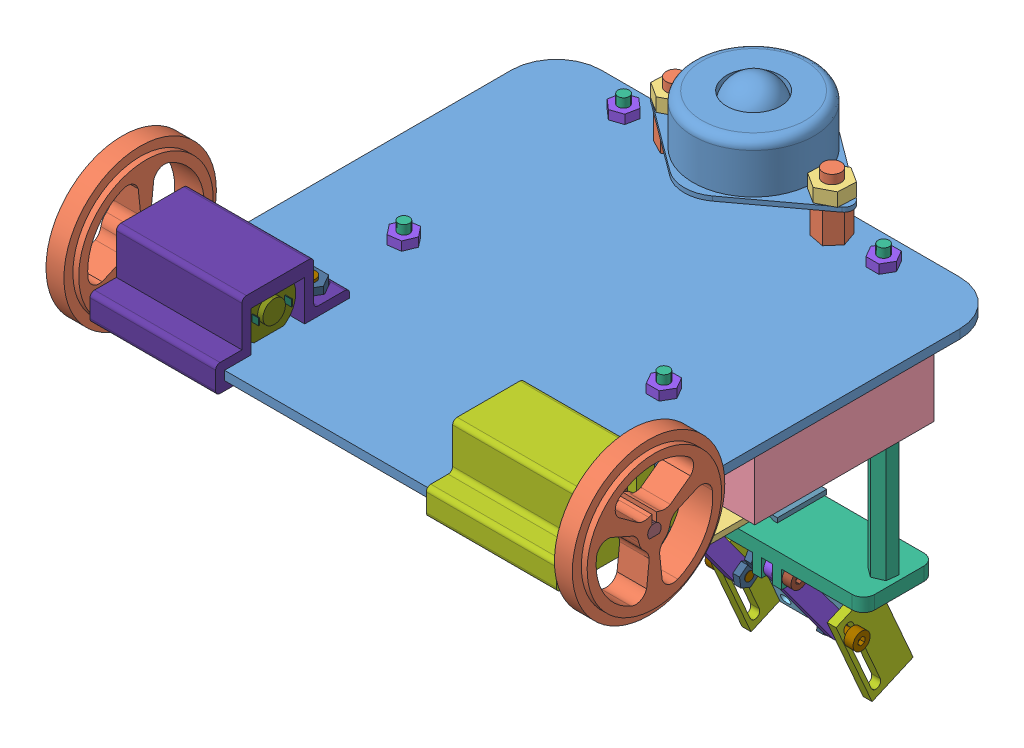
SolidWorks assembly car (old), configuration 默认. Lengths in mm.
Overall size (120 119.73 122.15).
122 component instances, 83 part files, 125 mates.
Components (placement in the parent):
- car  baseplate-3: car  baseplate [默认] at (1.828 99 14.0699) x (0 0 -1) z (0 1 0) size (100 100 2)
- N20 wheel -1: N20 wheel  [默认] at (61.828 106 52.1949) x (0 0 1) z (0 -1 0) size (34 8.6 34)
- N20 wheel -2: N20 wheel  [默认] at (-58.172 106 52.1949) x (0 0 1) z (0 1 0) size (34 8.6 34)
- raspberrypi3.stp-1: raspberrypi3.stp [默认] at (-8.172 78.45 0.8199) x (-1 0 0) z (0 0 -1) size (90.89 18.8 58.5)
  - Raspberry Pi 3.stp-1: Raspberry Pi 3.stp [默认] at origin size (90.89 18.8 58.5)
    - Raspberry Pi 3_1.stp-1: Raspberry Pi 3_1.stp [默认] at origin size (85 1.3 56)
    - Raspberry Pi 3_1_1.stp-1: Raspberry Pi 3_1_1.stp [默认] at origin size (14 1 14)
    - Raspberry Pi 3_2.stp-1: Raspberry Pi 3_2.stp [默认] at origin size (8.5 1 8.5)
    - Raspberry Pi 3_3.stp-1: Raspberry Pi 3_3.stp [默认] at origin size (12 1 12)
    - Raspberry Pi 3_4.stp-1: Raspberry Pi 3_4.stp [默认] at origin size (0.64 10.23 0.64)
    - Raspberry Pi 3_5.stp-1: Raspberry Pi 3_5.stp [默认] at origin size (0.64 10.23 0.64)
    - Raspberry Pi 3_6.stp-1: Raspberry Pi 3_6.stp [默认] at origin size (0.64 10.23 0.64)
    - Raspberry Pi 3_7.stp-1: Raspberry Pi 3_7.stp [默认] at origin size (0.64 10.23 0.64)
    - Raspberry Pi 3_8.stp-1: Raspberry Pi 3_8.stp [默认] at origin size (0.64 10.23 0.64)
    - Raspberry Pi 3_9.stp-1: Raspberry Pi 3_9.stp [默认] at origin size (0.64 10.23 0.64)
    - Raspberry Pi 3_10.stp-1: Raspberry Pi 3_10.stp [默认] at origin size (0.64 10.23 0.64)
    - Raspberry Pi 3_11.stp-1: Raspberry Pi 3_11.stp [默认] at origin size (0.64 10.23 0.64)
    - Raspberry Pi 3_12.stp-1: Raspberry Pi 3_12.stp [默认] at origin size (0.64 10.23 0.64)
    - Raspberry Pi 3_13.stp-1: Raspberry Pi 3_13.stp [默认] at origin size (0.64 10.23 0.64)
    - Raspberry Pi 3_14.stp-1: Raspberry Pi 3_14.stp [默认] at origin size (0.64 10.23 0.64)
    - Raspberry Pi 3_15.stp-1: Raspberry Pi 3_15.stp [默认] at origin size (0.64 10.23 0.64)
    - Raspberry Pi 3_16.stp-1: Raspberry Pi 3_16.stp [默认] at origin size (0.64 10.23 0.64)
    - Raspberry Pi 3_17.stp-1: Raspberry Pi 3_17.stp [默认] at origin size (0.64 10.23 0.64)
    - Raspberry Pi 3_18.stp-1: Raspberry Pi 3_18.stp [默认] at origin size (0.64 10.23 0.64)
    - Raspberry Pi 3_19.stp-1: Raspberry Pi 3_19.stp [默认] at origin size (0.64 10.23 0.64)
    - Raspberry Pi 3_20.stp-1: Raspberry Pi 3_20.stp [默认] at origin size (0.64 10.23 0.64)
    - Raspberry Pi 3_21.stp-1: Raspberry Pi 3_21.stp [默认] at origin size (0.64 10.23 0.64)
    - Raspberry Pi 3_22.stp-1: Raspberry Pi 3_22.stp [默认] at origin size (0.64 10.23 0.64)
    - Raspberry Pi 3_23.stp-1: Raspberry Pi 3_23.stp [默认] at origin size (0.64 10.23 0.64)
    - Raspberry Pi 3_24.stp-1: Raspberry Pi 3_24.stp [默认] at origin size (0.64 10.23 0.64)
    - Raspberry Pi 3_25.stp-1: Raspberry Pi 3_25.stp [默认] at origin size (0.64 10.23 0.64)
    - Raspberry Pi 3_26.stp-1: Raspberry Pi 3_26.stp [默认] at origin size (0.64 10.23 0.64)
    - Raspberry Pi 3_27.stp-1: Raspberry Pi 3_27.stp [默认] at origin size (0.64 10.23 0.64)
    - Raspberry Pi 3_28.stp-1: Raspberry Pi 3_28.stp [默认] at origin size (0.64 10.23 0.64)
    - Raspberry Pi 3_29.stp-1: Raspberry Pi 3_29.stp [默认] at origin size (0.64 10.23 0.64)
    - Raspberry Pi 3_30.stp-1: Raspberry Pi 3_30.stp [默认] at origin size (0.64 10.23 0.64)
    - Raspberry Pi 3_31.stp-1: Raspberry Pi 3_31.stp [默认] at origin size (0.64 10.23 0.64)
    - Raspberry Pi 3_32.stp-1: Raspberry Pi 3_32.stp [默认] at origin size (0.64 10.23 0.64)
    - Raspberry Pi 3_33.stp-1: Raspberry Pi 3_33.stp [默认] at origin size (0.64 10.23 0.64)
    - Raspberry Pi 3_34.stp-1: Raspberry Pi 3_34.stp [默认] at origin size (0.64 10.23 0.64)
    - Raspberry Pi 3_35.stp-1: Raspberry Pi 3_35.stp [默认] at origin size (0.64 10.23 0.64)
    - Raspberry Pi 3_36.stp-1: Raspberry Pi 3_36.stp [默认] at origin size (0.64 10.23 0.64)
    - Raspberry Pi 3_37.stp-1: Raspberry Pi 3_37.stp [默认] at origin size (0.64 10.23 0.64)
    - Raspberry Pi 3_38.stp-1: Raspberry Pi 3_38.stp [默认] at origin size (0.64 10.23 0.64)
    - Raspberry Pi 3_39.stp-1: Raspberry Pi 3_39.stp [默认] at origin size (0.64 10.23 0.64)
    - Raspberry Pi 3_40.stp-1: Raspberry Pi 3_40.stp [默认] at origin size (0.64 10.23 0.64)
    - Raspberry Pi 3_41.stp-1: Raspberry Pi 3_41.stp [默认] at origin size (0.64 10.23 0.64)
    - Raspberry Pi 3_42.stp-1: Raspberry Pi 3_42.stp [默认] at origin size (0.64 10.23 0.64)
    - Raspberry Pi 3_43.stp-1: Raspberry Pi 3_43.stp [默认] at origin size (0.64 10.23 0.64)
    - Raspberry Pi 3_44.stp-1: Raspberry Pi 3_44.stp [默认] at origin size (50.8 2.54 5.08)
    - Raspberry Pi 3_45.stp-1: Raspberry Pi 3_45.stp [默认] at origin size (3.91 5.48 22.4)
    - Raspberry Pi 3_46.stp-1: Raspberry Pi 3_46.stp [默认] at origin size (14 1.3 13)
    - Raspberry Pi 3 (micro SD).stp-1: Raspberry Pi 3 (micro SD).stp [默认] at origin size (15 1 11)
    - Raspberry Pi 3_47.stp-1: Raspberry Pi 3_47.stp [默认] at origin size (17.3 15.6 13.3)
    - Raspberry Pi 3_48.stp-1: Raspberry Pi 3_48.stp [默认] at origin size (3.91 5.48 22.4)
    - Raspberry Pi 3_49.stp-1: Raspberry Pi 3_49.stp [默认] at origin size (7.9 2.25 5)
    - Raspberry Pi 3_50.stp-1: Raspberry Pi 3_50.stp [默认] at origin size (15 8.38 11.55)
    - Raspberry Pi 3_51.stp-1: Raspberry Pi 3_51.stp [默认] at origin size (7 9 15)
    - Raspberry Pi 3_52.stp-1: Raspberry Pi 3_52.stp [默认] at origin size (21.4 15.3 16.02)
    - Raspberry Pi 3_53.stp-1: Raspberry Pi 3_53.stp [默认] at origin size (17.3 15.6 13.3)
    - RPi Heatsink Set.stp-1: RPi Heatsink Set.stp [默认] at origin size (14 6 14)
    - RPi Heatsink Set_1.stp-1: RPi Heatsink Set_1.stp [默认] at origin size (8.8 5 8.8)
- M2.5 28+6-13: M2.5 28+6 [默认] at (30.828 71 -29.9301) x (-0.540567 0 0.841301) z (-0.841301 0 -0.540567) size (4.87 34 5.26)
- M2.5 28+6-14: M2.5 28+6 [默认] at (30.828 71 19.0699) x (-0.717551 0 -0.696506) z (0.696506 0 -0.717551) size (4.87 34 5.26)
- M2.5 28+6-16: M2.5 28+6 [默认] at (-27.172 71 -29.9301) size (4.87 34 5.26)
- M2.5 28+6-17: M2.5 28+6 [默认] at (-27.172 71 19.0699) size (4.87 34 5.26)
- N20 lift mounting-1: N20 lift mounting [默认] at (51.828 106 52.1949) x (0 0 -1) z (1 0 0) size (29.88 16 29)
- M2.5 nut-1: M2.5 nut [默认] at (30.828 103 -29.9301) x (0.751714 0 -0.659489) z (0 -1 0) size (5.47 5.66 2)
- M3 8 hexagon socket head cap screw-1: M3 8 hexagon socket head cap screw [默认] at (48.828 94 40.1949) x (1 0 0) z (0 1 0) size (5.5 5.5 11)
- M3 nut-1: M3 nut [默认] at (48.828 104.4 40.1949) x (-0.195277 0 -0.980748) z (0 -1 0) size (6.01 6.23 2.4)
- N20 motor-1: N20 motor [默认] at (27.828 106 52.1949) x (0 0 -1) z (0 1 0) size (12 35.5 10)
  - User Library-N20(2)-1: User Library-N20(2) [默认] at origin size (12 35.5 10)
    - User Library-N20_Pad010^User Library-N20(2)-1: User Library-N20_Pad010^User Library-N20(2) [默认] at (0 -23 0) x (1 0 0) z (0 -1 0) size (12 10 2) (virtual)
    - User Library-N20_Pad009^User Library-N20(2)-1: User Library-N20_Pad009^User Library-N20(2) [默认] at (0 -15 0) x (1 0 0) z (0 -1 0) size (12 10 8.5) (virtual)
    - User Library-N20_Pad008-1: User Library-N20_Pad008 [默认] at (0 -1 0) x (1 0 0) z (0 -1 0) size (12 10 33)
    - User Library-N20_Pad006^User Library-N20(2)-1: User Library-N20_Pad006^User Library-N20(2) [默认] at (0 -18 0) x (1 0 0) z (0 -1 0) size (12 10 1) (virtual)
    - User Library-N20_Pad004^User Library-N20(2)-1: User Library-N20_Pad004^User Library-N20(2) [默认] x (1 0 0) z (0 -1 0) size (7.5 1.5 1.5) (virtual)
    - User Library-N20_Pad003^User Library-N20(2)-1: User Library-N20_Pad003^User Library-N20(2) [默认] x (1 0 0) z (0 -1 0) size (12 10 2.2) (virtual)
- N20 motor-2: N20 motor [默认] at (-24.172 106 52.1949) x (0 0 -1) z (0 -1 0) size (12 35.5 10)
  - User Library-N20(2)-1: User Library-N20(2) [默认] at origin size (12 35.5 10)
    - User Library-N20_Pad010^User Library-N20(2)-1: User Library-N20_Pad010^User Library-N20(2) [默认] at (0 -23 0) x (1 0 0) z (0 -1 0) size (12 10 2) (virtual)
    - User Library-N20_Pad009^User Library-N20(2)-1: User Library-N20_Pad009^User Library-N20(2) [默认] at (0 -15 0) x (1 0 0) z (0 -1 0) size (12 10 8.5) (virtual)
    - User Library-N20_Pad008-1: User Library-N20_Pad008 [默认] at (0 -1 0) x (1 0 0) z (0 -1 0) size (12 10 33)
    - User Library-N20_Pad006^User Library-N20(2)-1: User Library-N20_Pad006^User Library-N20(2) [默认] at (0 -18 0) x (1 0 0) z (0 -1 0) size (12 10 1) (virtual)
    - User Library-N20_Pad004^User Library-N20(2)-1: User Library-N20_Pad004^User Library-N20(2) [默认] x (1 0 0) z (0 -1 0) size (7.5 1.5 1.5) (virtual)
    - User Library-N20_Pad003^User Library-N20(2)-1: User Library-N20_Pad003^User Library-N20(2) [默认] x (1 0 0) z (0 -1 0) size (12 10 2.2) (virtual)
- N20 right mounting-1: N20 right mounting [默认] at (-48.172 106 52.1949) x (0 0 -1) z (-1 0 0) size (29.88 16 28)
- M2.5 nut-2: M2.5 nut [默认] at (30.828 101 19.0699) x (-0.946991 0 0.321259) z (0 1 0) size (5.47 5.66 2)
- M3 8 hexagon socket head cap screw-2: M3 8 hexagon socket head cap screw [默认] at (-45.172 94 40.1949) x (-0.740078 0 0.672521) z (0 1 0) size (5.5 5.5 11)
- M3 nut-2: M3 nut [默认] at (-45.172 104.4 40.1949) x (-0.195277 0 -0.980748) z (0 -1 0) size (6.01 6.23 2.4)
- M4 6 hexagon socket head cap screw-1: M4 6 hexagon socket head cap screw [默认] at (-15.672 99 -29.9301) x (-0.837169 0 -0.546944) z (0 -1 0) size (7 7 10)
- ball wheel-1: ball wheel [默认] at (1.828 108 -29.9301) x (0 0 1) z (-1 0 0) size (30.94 15 44.29)
- M4 7+6 copper cylinder-1: M4 7+6 copper cylinder [默认] at (-15.672 101 -29.9301) x (-0.648514 0 -0.761203) z (0 1 0) size (6.41 6.87 13)
- M4 7+6 copper cylinder-2: M4 7+6 copper cylinder [默认] at (19.328 101 -29.9301) x (-0.837169 0 -0.546944) z (0 1 0) size (6.41 6.87 13)
- M4 6 hexagon socket head cap screw-2: M4 6 hexagon socket head cap screw [默认] at (19.328 99 -29.9301) x (-0.837169 0 -0.546944) z (0 -1 0) size (7 7 10)
- M4 nut-1: M4 nut [默认] at (-15.672 112 -29.9301) x (1 0 0) z (0 -1 0) size (7.18 8.07 3)
- M4 nut-2: M4 nut [默认] at (19.328 112 -29.9301) x (1 0 0) z (0 -1 0) size (7.18 8.07 3)
- M2.5 nut-3: M2.5 nut [默认] at (-27.172 103 -29.9301) x (1 0 0) z (0 -1 0) size (5.47 5.66 2)
- M2.5 nut-4: M2.5 nut [默认] at (-27.172 101 19.0699) x (0.837169 0 0.546944) z (0 1 0) size (5.47 5.66 2)
- M2.5 28+6-18: M2.5 28+6 [默认] at (30.828 41.7 -29.9301) size (4.87 34 5.26)
- M2.5 28+6-19: M2.5 28+6 [默认] at (-27.172 41.7 -29.9301) x (0.98595 0 0.167042) z (-0.167042 0 0.98595) size (4.87 34 5.26)
- battery holder-1: battery holder [默认] at (7.8341 81 -5.1801) x (1 0 0) z (0 1 0) size (87 40 18)
- camera-1: camera [默认] at (1.8346 17.2443 -44.4669) x (-1 0 0) z (0 -0.401803 0.915726) size (25 24 7)
- camera base-1: camera base [默认] at (30.828 41.7 -34.4301) x (-1 0 0) z (0 -1 0) size (65 16 7)
- camera holder 1-1: camera holder 1 [默认] at (26.3313 40.475 -32.0897) x (1 0 0) z (0 -0.401803 0.915726) size (28.99 34.8 10)
- camera holder 2-1: camera holder 2 [默认] at (26.328 39.5522 -19.3623) x (1 0 0) z (0 -0.590859 0.806775) size (24 26.6 4)
- M3 8 hexagon socket head cap screw-3: M3 8 hexagon socket head cap screw [默认] at (29.828 94 40.1949) x (1 0 0) z (0 1 0) size (5.5 5.5 11)
- M3 nut-3: M3 nut [默认] at (29.828 102 40.1949) x (0.946991 0 -0.321259) z (0 1 0) size (6.01 6.23 2.4)
- M3 8 hexagon socket head cap screw-4: M3 8 hexagon socket head cap screw [默认] at (-27.172 94 40.1949) x (0.100908 0 -0.994896) z (0 1 0) size (5.5 5.5 11)
- M3 nut-4: M3 nut [默认] at (-27.172 104.4 40.1949) x (0.946991 0 0.321259) z (0 -1 0) size (6.01 6.23 2.4)
- M2 6 hexagon socket head cap screw-2: M2 6 hexagon socket head cap screw [默认] at (-12.6654 18.1442 -37.5199) x (0 0 1) z (-1 0 0) size (3.8 3.8 8)
- M2 6 hexagon socket head cap screw-3: M2 6 hexagon socket head cap screw [默认] at (16.328 18.1442 -37.5199) x (0 0.924225 0.381849) z (1 0 0) size (3.8 3.8 8)
- M2 nut-1: M2 nut [默认] at (-6.7654 18.1442 -37.5199) x (0 0 1) z (-1 0 0) size (4.27 4.58 1.5)
- M2 nut-2: M2 nut [默认] at (10.4214 18.1442 -37.5199) x (0 0 -1) z (1 0 0) size (4.27 4.58 1.5)
- M2 8 hexagon socket head cap screw-1: M2 8 hexagon socket head cap screw [默认] at (16.078 36.7 -23.9301) x (0 0.063311 -0.997994) z (1 0 0) size (3.8 3.8 10)
- M2 8 hexagon socket head cap screw-2: M2 8 hexagon socket head cap screw [默认] at (18.578 36.7 -35.9301) x (0 0.502781 0.864414) z (1 0 0) size (3.8 3.8 10)
- M2 8 hexagon socket head cap screw-3: M2 8 hexagon socket head cap screw [默认] at (-12.422 36.7 -23.9301) x (0 0.979053 0.203606) z (-1 0 0) size (3.8 3.8 10)
- M2 8 hexagon socket head cap screw-4: M2 8 hexagon socket head cap screw [默认] at (-14.922 36.7 -35.9301) x (0 0 1) z (-1 0 0) size (3.8 3.8 10)
- M2 nut-3: M2 nut [默认] at (-6.922 36.7 -35.9301) x (0 -0.381881 0.924211) z (-1 0 0) size (4.27 4.58 1.5)
- M2 nut-4: M2 nut [默认] at (8.078 36.7 -23.9301) x (0 0.60945 -0.792824) z (1 0 0) size (4.27 4.58 1.5)
- M2 nut-5: M2 nut [默认] at (10.578 36.7 -35.9301) x (0 -0.991331 -0.131387) z (1 0 0) size (4.27 4.58 1.5)
- M2 nut-6: M2 nut [默认] at (-5.922 36.7 -23.9301) x (0 0.60945 -0.792824) z (1 0 0) size (4.27 4.58 1.5)
Mates (geometry in assembly coordinates):
- 同心11: concentric: cylinder of assembly; cylinder of assembly; cylinder of M2.5 28+6-13 through (30.828 105 -29.9301) axis (0 -1 0) radius 1.25; cylinder of M2.5 nut-1 through (30.828 101 -29.9301) axis (0 1 0) radius 1.25
- 重合31: coincident: plane of assembly; plane of assembly; plane of N20 lift mounting-1 through (53.828 97 52.1949) normal (0 -1 0); plane of M3 8 hexagon socket head cap screw-1 through (48.828 97 40.1949) normal (0 1 0)
- 同心13: concentric: cylinder of assembly; cylinder of assembly; cylinder of M3 8 hexagon socket head cap screw-1 through (48.828 105 40.1949) axis (0 -1 0) radius 1.5; cylinder of M3 nut-1 through (48.828 102 40.1949) axis (0 1 0) radius 1.5
- 平行5: parallel: plane of assembly; plane of assembly; plane of N20 lift mounting-1 through (47.0959 113 43.1949) normal (0 0 -1); plane of M3 nut-1 through (50.4157 102 42.9449) normal (0 0 1)
- 重合41: coincident: plane of ? through (-8.172 71 -33.4301) normal (0 1 0); plane of M2.5 28+6-17 through (-27.172 71 19.0699) normal (0 -1 0)
- 重合42: coincident: plane of ? through (-8.172 71 -33.4301) normal (0 1 0); plane of M2.5 28+6-16 through (-27.172 71 -29.9301) normal (0 -1 0)
- 重合43: coincident: plane of ? through (-8.172 71 -33.4301) normal (0 1 0); plane of M2.5 28+6-13 through (30.828 71 -29.9301) normal (0 -1 0)
- 重合44: coincident: plane of ? through (-8.172 71 -33.4301) normal (0 1 0); plane of M2.5 28+6-14 through (30.828 71 19.0699) normal (0 -1 0)
- 重合45: coincident: plane of assembly; plane of assembly; plane of N20 lift mounting-1 through (51.828 106 52.1949) normal (-1 0 0); plane of N20 motor-1/User Library-N20(2)-1/User Library-N20_Pad010^User Library-N20(2)-1 through (51.828 101 57.1949) normal (1 0 0)
- 重合46: coincident: plane of assembly; plane of assembly; plane of N20 lift mounting-1 through (-11.0618 106 46.1949) normal (0 0 1); plane of N20 motor-1/User Library-N20(2)-1/User Library-N20_Pad010^User Library-N20(2)-1 through (50.828 102 46.1949) normal (0 0 -1)
- 重合47: coincident: plane of assembly; plane of assembly; plane of car  baseplate-3 through (41.828 101 -25.9301) normal (0 1 0); plane of N20 motor-1/User Library-N20(2)-1/User Library-N20_Pad008-1 through (28.828 101 55.5115) normal (0 -1 0)
- 重合48: coincident: plane of assembly; plane of assembly; plane of N20 wheel -1 through (55.228 105 53.3129) normal (0 1 0); plane of N20 motor-1/User Library-N20(2)-1/User Library-N20_Pad008-1 through (53.828 105 52.1949) normal (0 -1 0)
- 同心21: concentric: cylinder of assembly; cylinder of assembly; cylinder of N20 wheel -1 through (55.228 106 52.1949) axis (1 0 0) radius 1.5; cylinder of N20 motor-1/User Library-N20(2)-1/User Library-N20_Pad008-1 through (42.828 106 52.1949) axis (-1 0 0) radius 1.5
- 重合49: coincident: plane of assembly; plane of assembly; plane of N20 wheel -1 through (61.828 106 52.1949) normal (1 0 0); plane of N20 motor-1/User Library-N20(2)-1/User Library-N20_Pad008-1 through (61.828 106 50.6949) normal (1 0 0)
- 重合51: coincident: plane of assembly; plane of assembly; plane of car  baseplate-3 through (41.828 101 -25.9301) normal (0 1 0); plane of N20 motor-2/User Library-N20(2)-1/User Library-N20_Pad008-1 through (-25.172 101 48.8782) normal (0 -1 0)
- 平行6: parallel: plane of assembly; plane of assembly; plane of car  baseplate-3 through (-48.172 101 64.0699) normal (0 0 1); plane of N20 motor-2/User Library-N20(2)-1/User Library-N20_Pad010^User Library-N20(2)-1 through (-47.172 102 58.1949) normal (0 0 1)
- 重合54: coincident: plane of assembly; plane of assembly; plane of car  baseplate-3 through (-48.172 101 64.0699) normal (-1 0 0); plane of N20 motor-2/User Library-N20(2)-1/User Library-N20_Pad010^User Library-N20(2)-1 through (-48.172 111 57.1949) normal (-1 0 0)
- 重合55: coincident: plane of assembly; plane of assembly; plane of car  baseplate-3 through (51.828 101 64.0699) normal (1 0 0); plane of N20 motor-1/User Library-N20(2)-1/User Library-N20_Pad010^User Library-N20(2)-1 through (51.828 101 57.1949) normal (1 0 0)
- 距离1: distance = 5.875 mm: plane of assembly; plane of assembly; plane of N20 motor-2/User Library-N20(2)-1/User Library-N20_Pad010^User Library-N20(2)-1 through (-47.172 102 58.1949) normal (0 0 1); plane of car  baseplate-3 through (-48.172 101 64.0699) normal (0 0 1)
- 距离2: distance = 5.875 mm: plane of assembly; plane of assembly; plane of N20 motor-1/User Library-N20(2)-1/User Library-N20_Pad010^User Library-N20(2)-1 through (50.828 110 58.1949) normal (0 0 1); plane of car  baseplate-3 through (-48.172 101 64.0699) normal (0 0 1)
- 重合58: coincident: plane of assembly; plane of assembly; plane of N20 wheel -2 through (-51.572 107 53.3129) normal (0 -1 0); plane of N20 motor-2/User Library-N20(2)-1/User Library-N20_Pad008-1 through (-50.172 107 52.1949) normal (0 1 0)
- 同心22: concentric: cylinder of assembly; cylinder of assembly; cylinder of N20 wheel -2 through (-51.572 106 52.1949) axis (-1 0 0) radius 1.5; cylinder of N20 motor-2/User Library-N20(2)-1/User Library-N20_Pad008-1 through (-39.172 106 52.1949) axis (1 0 0) radius 1.5
- 重合59: coincident: plane of assembly; plane of assembly; plane of N20 wheel -2 through (-58.172 106 52.1949) normal (-1 0 0); plane of N20 motor-2/User Library-N20(2)-1/User Library-N20_Pad008-1 through (-58.172 106 50.6949) normal (-1 0 0)
- 在位1: in place: plane of ? through (-38.172 111 57.1949) normal (-1 0 0); plane of ? through (-38.172 0 0) normal (-1 0 0); moOrthogonalPlaneRef_w of ? through (-38.172 111 57.1949) normal (-1 0 0); plane of ? through (-38.172 0 0) normal (0 1 0); plane of ? through (-38.172 111 57.1949) normal (-1 0 0); plane of ? through (-38.172 0 0) normal (0 0 1); plane of N20 motor-2/User Library-N20(2)-1/User Library-N20_Pad010^User Library-N20(2)-1 through (-48.172 111 57.1949) normal (-1 0 0); unknown of N20 right mounting-1
- 重合60: coincident: plane of assembly; plane of assembly; plane of N20 motor-2/User Library-N20(2)-1/User Library-N20_Pad010^User Library-N20(2)-1; plane of N20 right mounting-1
- 重合61: coincident: plane of assembly; plane of assembly; moOrthogonalPlaneRef_w of N20 motor-2/User Library-N20(2)-1/User Library-N20_Pad010^User Library-N20(2)-1 through (-48.172 106 52.1949) normal (0 -1 0); plane of N20 right mounting-1 through (-48.172 106 52.1949) normal (0 -1 0)
- 重合62: coincident: plane of assembly; plane of assembly; moOrthogonalPlaneRef_w of N20 motor-2/User Library-N20(2)-1/User Library-N20_Pad010^User Library-N20(2)-1 through (-48.172 106 52.1949) normal (0 0 1); plane of N20 right mounting-1 through (-48.172 106 52.1949) normal (0 0 -1)
- 重合63: coincident: plane of assembly; plane of assembly; plane of N20 right mounting-1 through (-50.172 97 52.1949) normal (0 -1 0); plane of M3 8 hexagon socket head cap screw-2 through (-45.172 97 40.1949) normal (0 1 0)
- 同心24: concentric: cylinder of assembly; cylinder of assembly; cylinder of M3 8 hexagon socket head cap screw-2 through (-45.172 105 40.1949) axis (0 -1 0) radius 1.5; cylinder of M3 nut-2 through (-45.172 102 40.1949) axis (0 1 0) radius 1.5
- 同心25: concentric: cylinder of assembly; cylinder of assembly; cylinder of M2.5 28+6-14 through (30.828 105 19.0699) axis (0 -1 0) radius 1.25; cylinder of M2.5 nut-2 through (30.828 103 19.0699) axis (0 -1 0) radius 1.25
- 同心27: concentric: cylinder of assembly; cylinder of assembly; cylinder of ball wheel-1 through (19.328 109 -29.9301) axis (0 -1 0) radius 2; cylinder of M4 7+6 copper cylinder-2 through (19.328 114 -29.9301) axis (0 -1 0) radius 2
- 重合69: coincident: plane of assembly; plane of assembly; plane of ball wheel-1 through (1.828 108 -29.9301) normal (0 -1 0); plane of M4 7+6 copper cylinder-2 through (19.328 108 -29.9301) normal (0 1 0)
- 同心28: concentric: cylinder of assembly; cylinder of assembly; cylinder of car  baseplate-3 through (19.328 91 -29.9301) axis (0 1 0) radius 2.1; cylinder of M4 7+6 copper cylinder-2 through (19.328 105 -29.9301) axis (0 -1 0) radius 2
- 重合70: coincident: plane of assembly; plane of assembly; plane of car  baseplate-3 through (41.828 101 -25.9301) normal (0 1 0); plane of M4 7+6 copper cylinder-2 through (19.328 101 -29.9301) normal (0 -1 0)
- 同心32: concentric: cylinder of assembly; cylinder of assembly; cylinder of M4 7+6 copper cylinder-1 through (-15.672 114 -29.9301) axis (0 -1 0) radius 2; cylinder of ball wheel-1 through (-15.672 109 -29.9301) axis (0 -1 0) radius 2
- 重合71: coincident: plane of assembly; plane of assembly; plane of ball wheel-1 through (1.828 108 -29.9301) normal (0 -1 0); plane of M4 7+6 copper cylinder-1 through (-15.672 108 -29.9301) normal (0 1 0)
- 重合72: coincident: plane of assembly; plane of assembly; plane of car  baseplate-3 through (41.828 101 -25.9301) normal (0 1 0); plane of M4 7+6 copper cylinder-1 through (-15.672 101 -29.9301) normal (0 -1 0)
- 同心33: concentric: cylinder of assembly; cylinder of assembly; cylinder of M4 6 hexagon socket head cap screw-1 through (-15.672 105 -29.9301) axis (0 -1 0) radius 2; cylinder of M4 7+6 copper cylinder-1 through (-15.672 105 -29.9301) axis (0 -1 0) radius 2
- 重合73: coincident: plane of assembly; plane of assembly; plane of car  baseplate-3 through (41.828 99 -25.9301) normal (0 -1 0); plane of M4 6 hexagon socket head cap screw-1 through (-15.672 99 -29.9301) normal (0 1 0)
- 同心34: concentric: cylinder of assembly; cylinder of assembly; cylinder of M4 7+6 copper cylinder-2 through (19.328 105 -29.9301) axis (0 -1 0) radius 2; cylinder of M4 6 hexagon socket head cap screw-2 through (19.328 105 -29.9301) axis (0 -1 0) radius 2
- 重合74: coincident: plane of assembly; plane of assembly; plane of car  baseplate-3 through (41.828 99 -25.9301) normal (0 -1 0); plane of M4 6 hexagon socket head cap screw-2 through (19.328 99 -29.9301) normal (0 1 0)
- 同心35: concentric: cylinder of assembly; cylinder of assembly; cylinder of M4 7+6 copper cylinder-1 through (-15.672 114 -29.9301) axis (0 -1 0) radius 2; cylinder of M4 nut-1 through (-15.672 109 -29.9301) axis (0 1 0) radius 2
- 重合75: coincident: plane of assembly; plane of assembly; plane of ball wheel-1 through (1.828 109 -29.9301) normal (0 1 0); plane of M4 nut-1 through (-15.672 109 -29.9301) normal (0 -1 0)
- 同心36: concentric: cylinder of assembly; cylinder of assembly; cylinder of M4 7+6 copper cylinder-2 through (19.328 114 -29.9301) axis (0 -1 0) radius 2; cylinder of M4 nut-2 through (19.328 109 -29.9301) axis (0 1 0) radius 2
- 重合76: coincident: plane of assembly; plane of assembly; plane of ball wheel-1 through (1.828 109 -29.9301) normal (0 1 0); plane of M4 nut-2 through (19.328 109 -29.9301) normal (0 -1 0)
- 同心37: concentric: cylinder of assembly; cylinder of assembly; cylinder of M2.5 28+6-17 through (-27.172 105 19.0699) axis (0 -1 0) radius 1.25; cylinder of M2.5 nut-4 through (-27.172 103 19.0699) axis (0 -1 0) radius 1.25
- 重合77: coincident: plane of assembly; plane of assembly; plane of car  baseplate-3 through (41.828 101 -25.9301) normal (0 1 0); plane of M2.5 nut-4 through (-27.172 101 19.0699) normal (0 -1 0)
- 同心38: concentric: cylinder of assembly; cylinder of assembly; cylinder of M2.5 28+6-16 through (-27.172 105 -29.9301) axis (0 -1 0) radius 1.25; cylinder of M2.5 nut-3 through (-27.172 101 -29.9301) axis (0 1 0) radius 1.25
- 重合78: coincident: plane of assembly; plane of assembly; plane of car  baseplate-3 through (41.828 101 -25.9301) normal (0 1 0); plane of M2.5 nut-3 through (-27.172 101 -29.9301) normal (0 -1 0)
- 同心40: concentric: cylinder of assembly; cylinder of assembly; cylinder of M2.5 28+6-16 through (-27.172 77 -29.9301) axis (0 -1 0) radius 1.25; cylinder of M2.5 28+6-19 through (-27.172 75.7 -29.9301) axis (0 -1 0) radius 1.25
- 重合80: coincident: plane of ? through (34.328 69.7 -5.4301) normal (0 -1 0); plane of M2.5 28+6-19 through (-27.172 69.7 -29.9301) normal (0 1 0)
- 同心41: concentric: cylinder of assembly; cylinder of assembly; cylinder of M2.5 28+6-13 through (30.828 77 -29.9301) axis (0 -1 0) radius 1.25; cylinder of M2.5 28+6-18 through (30.828 75.7 -29.9301) axis (0 -1 0) radius 1.25
- 重合81: coincident: plane of ? through (34.328 69.7 -5.4301) normal (0 -1 0); plane of M2.5 28+6-18 through (30.828 69.7 -29.9301) normal (0 1 0)
- 同心44: concentric: cylinder of assembly; cylinder of assembly; cylinder of camera-1 through (-8.6654 7.6853 -47.5692) axis (0 0.401803 -0.915726) radius 1.1; cylinder of camera holder 1-1 through (-8.6654 8.0871 -48.485) axis (0 0.401803 -0.915726) radius 1
- 平行11: parallel: plane of assembly; plane of assembly; plane of camera-1 through (14.3346 5.8538 -48.3728) normal (0 -0.915726 -0.401803); plane of camera holder 1-1 through (16.328 7.2846 -51.0211) normal (0 -0.915726 -0.401803)
- 重合111: coincident: plane of assembly; plane of assembly; plane of camera-1 through (1.8346 17.2443 -44.4669) normal (0 0.401803 -0.915726); plane of camera holder 1-1 through (26.3313 41.2786 -33.9211) normal (0 -0.401803 0.915726)
- 重合112: coincident: plane of assembly; plane of assembly; plane of camera-1 through (1.8346 17.2443 -44.4669) normal (0 0.401803 -0.915726); plane of camera holder 1-1 through (26.3313 41.2786 -33.9211) normal (0 -0.401803 0.915726)
- 同心48: concentric: cylinder of assembly; cylinder of assembly; cylinder of camera base-1 through (-30.672 36.7 -35.9301) axis (1 0 0) radius 1.1; cylinder of camera holder 1-1 through (-12.6654 36.7 -35.9301) axis (1 0 0) radius 1
- 同心49: concentric: cylinder of assembly; cylinder of assembly; cylinder of camera base-1 through (-30.672 36.7 -35.9301) axis (1 0 0) radius 1.1; cylinder of camera holder 1-1 through (-12.6654 36.7 -35.9301) axis (1 0 0) radius 1
- 同心50: concentric: cylinder of assembly; cylinder of assembly; cylinder of camera base-1 through (-30.672 36.7 -23.9301) axis (1 0 0) radius 1.1; cylinder of camera holder 2-1 through (-10.172 36.7 -23.9301) axis (1 0 0) radius 1.1
- 同心51: concentric: cylinder of assembly; cylinder of assembly; cylinder of camera base-1 through (-30.672 36.7 -23.9301) axis (1 0 0) radius 1.1; cylinder of camera holder 2-1 through (-10.172 36.7 -23.9301) axis (1 0 0) radius 1.1
- 平行12: parallel: plane of assembly; plane of assembly; plane of camera holder 1-1 through (14.328 39.3351 -36.958) normal (-1 0 0); plane of camera holder 2-1 through (13.828 41.9156 -22.5894) normal (1 0 0)
- 相切1: tangent: plane of assembly; cylinder of assembly; plane of camera holder 1-1 through (-12.6654 39.3098 -29.4341) normal (0 -0.401803 0.915726); cylinder of camera holder 2-1 through (-10.172 18.1442 -37.5199) axis (1 0 0) radius 1.1
- 距离6: distance = 0.25 mm: plane of assembly; plane of assembly; plane of camera holder 2-1 through (13.828 41.9156 -22.5894) normal (1 0 0); plane of camera base-1 through (14.078 34.7 -34.4301) normal (-1 0 0)
- 距离7: distance = 0.25 mm: plane of assembly; plane of assembly; plane of camera holder 1-1 through (14.328 39.3351 -36.958) normal (-1 0 0); plane of camera base-1 through (14.078 34.7 -34.4301) normal (1 0 0)
- LimitDistance1: limit distance = 0.0692 mm: cylinder of assembly; cylinder of assembly; cylinder of camera holder 2-1 through (-10.172 18.1442 -37.5199) axis (1 0 0) radius 1.1; cylinder of camera holder 1-1 through (-12.6654 20.0954 -36.6637) axis (1 0 0) radius 1.1
- 重合115: coincident: plane of assembly; plane of assembly; plane of car  baseplate-3 through (41.828 99 -25.9301) normal (0 -1 0); plane of M2.5 28+6-13 through (30.828 99 -29.9301) normal (0 1 0)
- 重合119: coincident: plane of assembly; plane of assembly; plane of car  baseplate-3 through (41.828 99 -25.9301) normal (0 -1 0); plane of battery holder-1 through (7.8341 99 -5.1801) normal (0 1 0)
- 距离13: distance = 3 mm: plane of assembly; cylinder of assembly; plane of battery holder-1 through (-31.1659 99 14.8199) normal (0 0 1); cylinder of M2.5 28+6-17 through (-27.172 105 19.0699) axis (0 -1 0) radius 1.25
- 重合121: coincident: plane of assembly; plane of assembly; plane of M2.5 28+6-18 through (30.828 41.7 -29.9301) normal (0 -1 0); plane of camera base-1 through (30.828 41.7 -34.4301) normal (0 1 0)
- 重合122: coincident: plane of assembly; plane of assembly; plane of car  baseplate-3 through (41.828 101 -25.9301) normal (0 1 0); plane of N20 lift mounting-1 through (-11.0618 101 52.1949) normal (0 -1 0)
- 同心52: concentric: cylinder of assembly; cylinder of assembly; cylinder of car  baseplate-3 through (30.828 99 -29.9301) axis (0 1 0) radius 1.35; cylinder of M2.5 28+6-13 through (30.828 105 -29.9301) axis (0 -1 0) radius 1.25
- 同心53: concentric: cylinder of assembly; cylinder of assembly; cylinder of car  baseplate-3 through (-27.172 99 19.0699) axis (0 1 0) radius 1.35; cylinder of M2.5 28+6-17 through (-27.172 105 19.0699) axis (0 -1 0) radius 1.25
- 重合124: coincident: plane of assembly; plane of assembly; plane of car  baseplate-3 through (41.828 101 -25.9301) normal (0 1 0); plane of M2.5 nut-1 through (30.828 101 -29.9301) normal (0 -1 0)
- 重合126: coincident: plane of assembly; plane of assembly; plane of car  baseplate-3 through (41.828 101 -25.9301) normal (0 1 0); plane of M2.5 nut-2 through (30.828 101 19.0699) normal (0 -1 0)
- 同心54: concentric: cylinder of assembly; cylinder of assembly; cylinder of N20 lift mounting-1 through (48.828 97 40.1949) axis (0 1 0) radius 1.6; cylinder of M3 8 hexagon socket head cap screw-1 through (48.828 105 40.1949) axis (0 -1 0) radius 1.5
- 重合127: coincident: plane of assembly; plane of assembly; plane of N20 lift mounting-1 through (51.828 102 52.1949) normal (0 1 0); plane of M3 nut-1 through (48.828 102 40.1949) normal (0 -1 0)
- 同心55: concentric: cylinder of assembly; cylinder of assembly; cylinder of N20 right mounting-1 through (-45.172 97 40.1949) axis (0 1 0) radius 1.6; cylinder of M3 8 hexagon socket head cap screw-2 through (-45.172 105 40.1949) axis (0 -1 0) radius 1.5
- 重合128: coincident: plane of assembly; plane of assembly; plane of N20 right mounting-1 through (-48.172 102 52.1949) normal (0 1 0); plane of M3 nut-2 through (-45.172 102 40.1949) normal (0 -1 0)
- 平行19: parallel: plane of assembly; plane of assembly; plane of N20 right mounting-1 through (-48.172 102 43.1949) normal (0 0 -1); plane of M3 nut-2 through (-46.7597 102 37.4449) normal (0 0 -1)
- 同心56: concentric: cylinder of assembly; cylinder of assembly; cylinder of M2.5 28+6-19 through (-27.172 47.7 -29.9301) axis (0 -1 0) radius 1.25; cylinder of camera base-1 through (-27.172 38.7 -29.9301) axis (0 1 0) radius 1.3
- 同心57: concentric: cylinder of assembly; circle of assembly; cylinder of M2.5 28+6-18 through (30.828 47.7 -29.9301) axis (0 -1 0) radius 1.25; circle of camera base-1
- 距离14: distance = 2 mm: plane of battery holder-1 through (-31.1659 99 -25.1801) normal (-1 0 0); plane of ? through (-33.1659 78.65 -31.1801) normal (1 0 0)
- 平行20: parallel: plane of car  baseplate-3 through (-48.172 101 64.0699) normal (0 0 1); plane of ? through (-8.172 69.7 -33.4301) normal (0 0 -1)
- 同心59: concentric: cylinder of ? through (-27.172 69.7 -29.9301) axis (0 1 0) radius 1.25; cylinder of M2.5 28+6-19 through (-27.172 75.7 -29.9301) axis (0 -1 0) radius 1.25
- 同心60: concentric: cylinder of ? through (30.828 69.7 19.0699) axis (0 1 0) radius 1.25; cylinder of M2.5 28+6-14 through (30.828 77 19.0699) axis (0 -1 0) radius 1.25
- 同心61: concentric: cylinder of assembly; cylinder of assembly; cylinder of N20 lift mounting-1 through (29.828 97 40.1949) axis (0 1 0) radius 1.6; cylinder of M3 8 hexagon socket head cap screw-3 through (29.828 105 40.1949) axis (0 -1 0) radius 1.5
- 重合130: coincident: plane of assembly; plane of assembly; plane of N20 lift mounting-1 through (53.828 97 52.1949) normal (0 -1 0); plane of M3 8 hexagon socket head cap screw-3 through (29.828 97 40.1949) normal (0 1 0)
- 重合131: coincident: plane of assembly; plane of assembly; plane of N20 lift mounting-1 through (51.828 102 52.1949) normal (0 1 0); plane of M3 nut-3 through (29.828 102 40.1949) normal (0 -1 0)
- 同心62: concentric: cylinder of assembly; cylinder of assembly; cylinder of M3 nut-3 through (29.828 104.4 40.1949) axis (0 -1 0) radius 1.5; cylinder of M3 8 hexagon socket head cap screw-3 through (29.828 105 40.1949) axis (0 -1 0) radius 1.5
- 平行21: parallel: plane of assembly; plane of assembly; plane of N20 lift mounting-1 through (31.56 113 37.1949) normal (0 0 1); plane of M3 nut-3 through (31.4157 104.4 37.4449) normal (0 0 -1)
- 同心63: concentric: cylinder of assembly; cylinder of assembly; cylinder of N20 right mounting-1 through (-27.172 97 40.1949) axis (0 1 0) radius 1.6; cylinder of M3 8 hexagon socket head cap screw-4 through (-27.172 105 40.1949) axis (0 -1 0) radius 1.5
- 重合134: coincident: plane of assembly; plane of assembly; plane of N20 right mounting-1 through (-50.172 97 52.1949) normal (0 -1 0); plane of M3 8 hexagon socket head cap screw-4 through (-27.172 97 40.1949) normal (0 1 0)
- 同心64: concentric: cylinder of assembly; cylinder of assembly; cylinder of M3 8 hexagon socket head cap screw-4 through (-27.172 105 40.1949) axis (0 -1 0) radius 1.5; cylinder of M3 nut-4 through (-27.172 102 40.1949) axis (0 1 0) radius 1.5
- 平行22: parallel: plane of assembly; plane of assembly; plane of N20 right mounting-1 through (-48.172 113 43.1949) normal (0 0 -1); plane of M3 nut-4 through (-28.7597 102 37.4449) normal (0 0 -1)
- 重合136: coincident: plane of assembly; plane of assembly; plane of N20 right mounting-1 through (-48.172 102 52.1949) normal (0 1 0); plane of M3 nut-4 through (-27.172 102 40.1949) normal (0 -1 0)
- 同心66: concentric: cylinder of assembly; cylinder of assembly; cylinder of camera holder 2-1 through (-10.172 18.1442 -37.5199) axis (1 0 0) radius 1.1; cylinder of M2 6 hexagon socket head cap screw-2 through (-6.6654 18.1442 -37.5199) axis (-1 0 0) radius 1
- 重合138: coincident: plane of assembly; plane of assembly; plane of camera holder 1-1 through (-12.6654 39.3351 -36.958) normal (-1 0 0); plane of M2 6 hexagon socket head cap screw-2 through (-12.6654 18.1442 -37.5199) normal (1 0 0)
- 同心67: concentric: cylinder of assembly; cylinder of assembly; cylinder of camera holder 2-1 through (-10.172 18.1442 -37.5199) axis (1 0 0) radius 1.1; cylinder of M2 6 hexagon socket head cap screw-3 through (10.328 18.1442 -37.5199) axis (1 0 0) radius 1
- 重合139: coincident: plane of assembly; plane of assembly; plane of camera holder 1-1 through (16.328 39.3351 -36.958) normal (1 0 0); plane of M2 6 hexagon socket head cap screw-3 through (16.328 18.1442 -37.5199) normal (-1 0 0)
- 同心68: concentric: cylinder of assembly; cylinder of assembly; cylinder of M2 6 hexagon socket head cap screw-2 through (-6.6654 18.1442 -37.5199) axis (-1 0 0) radius 1; cylinder of M2 nut-1 through (-8.2654 18.1442 -37.5199) axis (1 0 0) radius 1
- 重合140: coincident: plane of assembly; plane of assembly; plane of camera holder 2-1 through (-8.2654 41.9156 -22.5894) normal (1 0 0); plane of M2 nut-1 through (-8.2654 18.1442 -37.5199) normal (-1 0 0)
- 同心69: concentric: cylinder of assembly; cylinder of assembly; cylinder of M2 6 hexagon socket head cap screw-3 through (10.328 18.1442 -37.5199) axis (1 0 0) radius 1; cylinder of M2 nut-2 through (11.9214 18.1442 -37.5199) axis (-1 0 0) radius 1
- 重合141: coincident: plane of assembly; plane of assembly; plane of camera holder 2-1 through (11.9214 41.9156 -22.5894) normal (-1 0 0); plane of M2 nut-2 through (11.9214 18.1442 -37.5199) normal (1 0 0)
- 同心70: concentric: cylinder of assembly; cylinder of assembly; cylinder of camera holder 1-1 through (-12.6654 36.7 -35.9301) axis (1 0 0) radius 1; cylinder of M2 8 hexagon socket head cap screw-4 through (-6.922 36.7 -35.9301) axis (-1 0 0) radius 1
- 重合142: coincident: plane of assembly; plane of assembly; plane of camera base-1 through (-14.922 34.7 -34.4301) normal (-1 0 0); plane of M2 8 hexagon socket head cap screw-4 through (-14.922 36.7 -35.9301) normal (1 0 0)
- 同心71: concentric: cylinder of assembly; cylinder of assembly; cylinder of camera holder 1-1 through (-12.6654 36.7 -35.9301) axis (1 0 0) radius 1; cylinder of M2 8 hexagon socket head cap screw-2 through (10.578 36.7 -35.9301) axis (1 0 0) radius 1
- 重合143: coincident: plane of assembly; plane of assembly; plane of camera base-1 through (18.578 34.7 -34.4301) normal (1 0 0); plane of M2 8 hexagon socket head cap screw-2 through (18.578 36.7 -35.9301) normal (-1 0 0)
- 同心73: concentric: cylinder of assembly; cylinder of assembly; cylinder of camera holder 2-1 through (-10.172 36.7 -23.9301) axis (1 0 0) radius 1.1; cylinder of M2 8 hexagon socket head cap screw-1 through (8.078 36.7 -23.9301) axis (1 0 0) radius 1
- 重合144: coincident: plane of assembly; plane of assembly; plane of camera base-1 through (16.078 34.7 -34.4301) normal (1 0 0); plane of M2 8 hexagon socket head cap screw-1 through (16.078 36.7 -23.9301) normal (-1 0 0)
- 同心74: concentric: cylinder of assembly; cylinder of assembly; cylinder of camera holder 2-1 through (-10.172 36.7 -23.9301) axis (1 0 0) radius 1.1; cylinder of M2 8 hexagon socket head cap screw-3 through (-4.422 36.7 -23.9301) axis (-1 0 0) radius 1
- 重合145: coincident: plane of assembly; plane of assembly; plane of camera base-1 through (-12.422 34.7 -34.4301) normal (-1 0 0); plane of M2 8 hexagon socket head cap screw-3 through (-12.422 36.7 -23.9301) normal (1 0 0)
- 同心75: concentric: cylinder of assembly; cylinder of assembly; cylinder of M2 8 hexagon socket head cap screw-4 through (-6.922 36.7 -35.9301) axis (-1 0 0) radius 1; cylinder of M2 nut-3 through (-8.422 36.7 -35.9301) axis (1 0 0) radius 1
- 重合146: coincident: plane of assembly; plane of assembly; plane of camera base-1 through (-8.422 34.7 -34.4301) normal (1 0 0); plane of M2 nut-3 through (-8.422 36.7 -35.9301) normal (-1 0 0)
- 同心76: concentric: cylinder of assembly; cylinder of assembly; cylinder of car  baseplate-3 through (30.828 99 19.0699) axis (0 1 0) radius 1.35; cylinder of M2.5 28+6-14 through (30.828 105 19.0699) axis (0 -1 0) radius 1.25
- 同心77: concentric: cylinder of assembly; cylinder of assembly; cylinder of M2 8 hexagon socket head cap screw-2 through (10.578 36.7 -35.9301) axis (1 0 0) radius 1; cylinder of M2 nut-5 through (12.078 36.7 -35.9301) axis (-1 0 0) radius 1
- 重合147: coincident: plane of assembly; plane of assembly; plane of camera base-1 through (12.078 34.7 -34.4301) normal (-1 0 0); plane of M2 nut-5 through (12.078 36.7 -35.9301) normal (1 0 0)
- 同心78: concentric: cylinder of assembly; cylinder of assembly; cylinder of M2 8 hexagon socket head cap screw-1 through (8.078 36.7 -23.9301) axis (1 0 0) radius 1; cylinder of M2 nut-4 through (9.578 36.7 -23.9301) axis (-1 0 0) radius 1
- 重合148: coincident: plane of assembly; plane of assembly; plane of camera base-1 through (9.578 34.7 -34.4301) normal (-1 0 0); plane of M2 nut-4 through (9.578 36.7 -23.9301) normal (1 0 0)
- 同心79: concentric: cylinder of assembly; cylinder of assembly; cylinder of M2 8 hexagon socket head cap screw-3 through (-4.422 36.7 -23.9301) axis (-1 0 0) radius 1; cylinder of M2 nut-6 through (-4.422 36.7 -23.9301) axis (-1 0 0) radius 1
- 重合149: coincident: plane of assembly; plane of assembly; plane of camera base-1 through (-5.922 34.7 -34.4301) normal (1 0 0); plane of M2 nut-6 through (-5.922 36.7 -23.9301) normal (-1 0 0)
- 平行23: parallel: plane of assembly; plane of assembly; plane of camera base-1 through (30.828 38.7 -34.4301) normal (0 -1 0); plane of M2 nut-6 through (-4.422 34.7 -22.7754) normal (0 -1 0)
- 平行24: parallel: plane of assembly; plane of assembly; plane of camera base-1 through (30.828 38.7 -34.4301) normal (0 -1 0); plane of M2 nut-3 through (-8.422 34.7 -37.0848) normal (0 -1 0)
- 平行25: parallel: plane of assembly; plane of assembly; plane of camera base-1 through (30.828 38.7 -34.4301) normal (0 -1 0); plane of M2 nut-5 through (12.078 34.7 -34.7754) normal (0 -1 0)
- 平行26: parallel: plane of assembly; plane of assembly; plane of camera base-1 through (30.828 38.7 -34.4301) normal (0 -1 0); plane of M2 nut-4 through (9.578 34.7 -22.7754) normal (0 -1 0)
